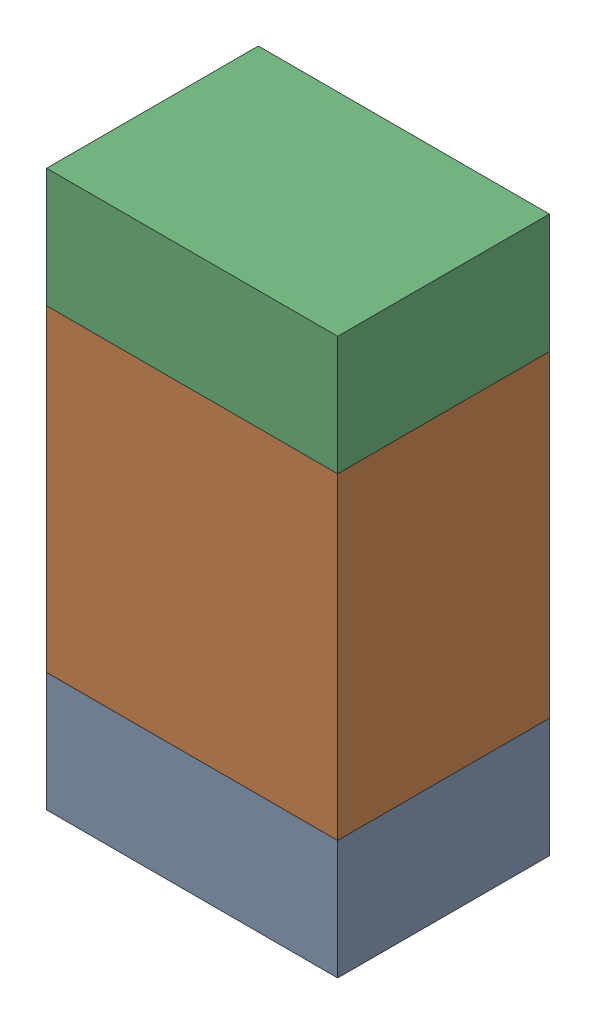
SolidWorks assembly R605_3PCB, configuration Default. Lengths in mm.
Overall size (0.55 1.05 0.4).
6 component instances, 2 part files, 0 mates.
Components (placement in the parent):
- 846483288-1: 846483288 [Default] at (100.4001 93.6876 -2.0638) size (0.55 0.22 0.4)
  - Extruded_12-1: Extruded_12 [Default] at origin size (0.55 0.22 0.4)
- 846483424-1: 846483424 [Default] at (100.4001 94.1001 -2.0638) size (0.55 0.6 0.4)
  - Extruded_13-1: Extruded_13 [Default] at origin size (0.55 0.6 0.4)
- 846483288-2: 846483288 [Default] at (100.4001 94.5126 -2.0638) size (0.55 0.22 0.4)
  - Extruded_12-1: Extruded_12 [Default] at origin size (0.55 0.22 0.4)
